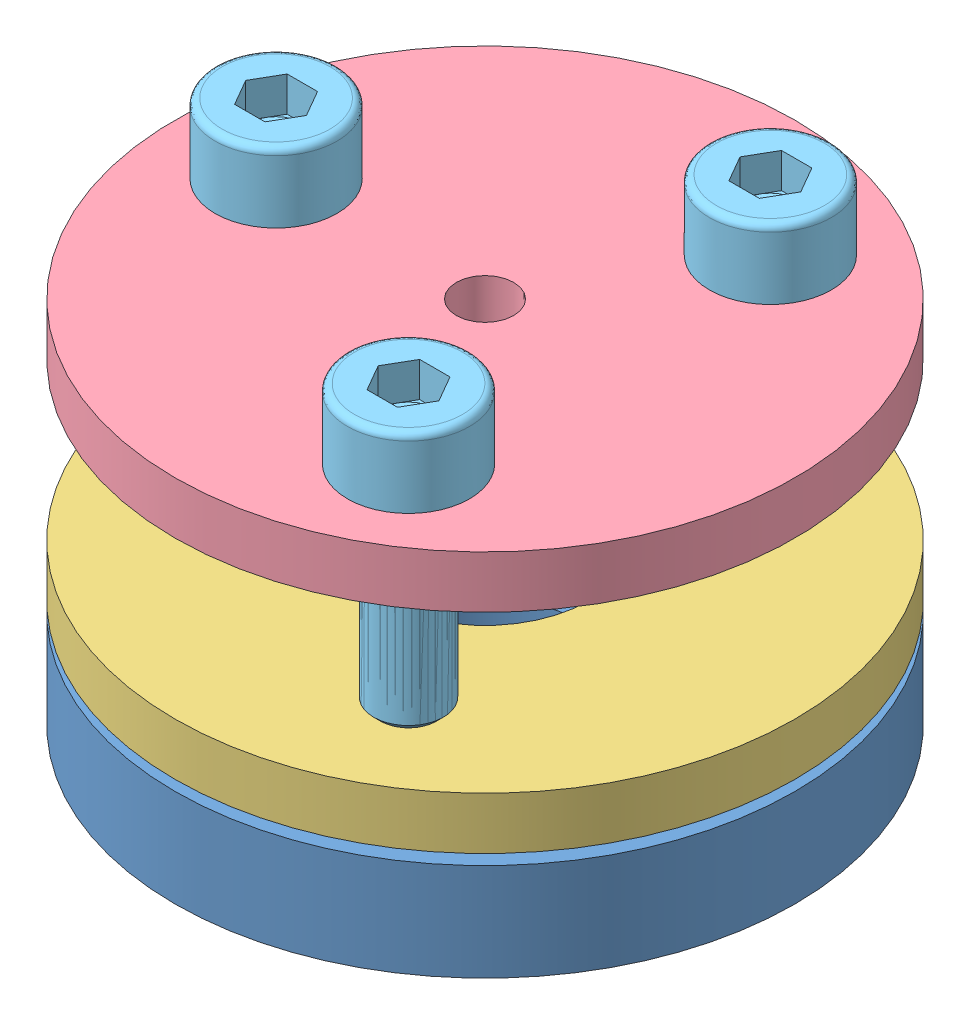
SolidWorks assembly a-spanner-wirbelsäule-v01, configuration 01. Lengths in mm.
Overall size (35.6 25.2 35.6).
8 component instances, 5 part files, 17 mates.
Components (placement in the parent):
- p-federträger-v01-1: p-federträger-v01 [01] at origin size (35.6 5.6 35.6)
- n-tellerfeder-knörzer-A0315-1: n-tellerfeder-knörzer-A0315 [01] at (0 2 0) size (31.5 2.1 31.5)
- n-tellerfeder-knörzer-A0315-2: n-tellerfeder-knörzer-A0315 [01] at (0 6.2 0) x (-1 0 0) z (0 0 1) size (31.5 2.1 31.5)
- p-stützscheibe-v01-1: p-stützscheibe-v01 [01] at (0 6.2 0) size (35.6 3 35.6)
- p-spannscheibe-v01-1: p-spannscheibe-v01 [01] at (0 18.2 0) size (35.6 3 35.6)
- zyl-schr-i6kt-M4x12 (BN4)-5: zyl-schr-i6kt-M4x12 (BN4) [zyl-schr-i6kt-M4x12 (BN4)] at (-12 25.2 0) x (0 -1 0) z (0 0 1) size (16 7 7)
- zyl-schr-i6kt-M4x12 (BN4)-6: zyl-schr-i6kt-M4x12 (BN4) [zyl-schr-i6kt-M4x12 (BN4)] at (6 25.2 -10.3923) x (0 -1 0) z (0 0 1) size (16 7 7)
- zyl-schr-i6kt-M4x12 (BN4)-7: zyl-schr-i6kt-M4x12 (BN4) [zyl-schr-i6kt-M4x12 (BN4)] at (6 25.2 10.3923) x (0 -1 0) z (0 0 1) size (16 7 7)
Mates (geometry in assembly coordinates):
- Deckungsgleich1: coincident anti-aligned: plane of p-federträger-v01-1 through (0 2 15.9) normal (0 1 0); circle of n-tellerfeder-knörzer-A0315-1
- Konzentrisch1: concentric aligned: cylinder of p-federträger-v01-1 through (0 0 0) axis (0 -1 0) radius 15.9; cone of n-tellerfeder-knörzer-A0315-1 through (0 3.7481 0) axis (0 -1 0)
- Parallel1: parallel aligned: plane of n-tellerfeder-knörzer-A0315-1 through (0 2 0) normal (1 0 0); plane of assembly through (0 0 0) normal (1 0 0)
- Deckungsgleich3: coincident anti-aligned: circle of n-tellerfeder-knörzer-A0315-1; circle of n-tellerfeder-knörzer-A0315-2
- Parallel2: parallel anti-aligned: plane of n-tellerfeder-knörzer-A0315-2; plane of assembly through (0 0 0) normal (1 0 0)
- Konzentrisch2: concentric anti-aligned: cone of n-tellerfeder-knörzer-A0315-2 through (0 5.8481 0) axis (0 1 0); cylinder of p-stützscheibe-v01-1 through (0 6.2 0) axis (0 -1 0) radius 6
- Parallel3: parallel aligned: plane of p-stützscheibe-v01-1 through (0 6.2 0) normal (1 0 0); plane of assembly through (0 0 0) normal (1 0 0)
- Abstand1: distance = 9 mm anti-aligned: plane of p-spannscheibe-v01-1 through (0 18.2 1) normal (0 -1 0); plane of p-stützscheibe-v01-1 through (0 9.2 6) normal (0 1 0)
- Konzentrisch3: concentric aligned: cylinder of p-federträger-v01-1 through (0 0 0) axis (0 -1 0) radius 17.8; cylinder of p-spannscheibe-v01-1 through (0 18.2 0) axis (0 -1 0) radius 17.8
- Parallel4: parallel aligned: plane of p-spannscheibe-v01-1 through (0 18.2 0) normal (1 0 0); plane of assembly through (0 0 0) normal (1 0 0)
- Konzentrisch4: concentric aligned: cylinder of p-spannscheibe-v01-1 through (6 21.2 10.3923) axis (0 1 0) radius 1.65; cylinder of zyl-schr-i6kt-M4x12 (BN4)-7 through (6 56.95 10.3923) axis (0 1 0) radius 2
- Deckungsgleich6: coincident anti-aligned: plane of p-stützscheibe-v01-1 through (0 9.2 6) normal (0 1 0); plane of zyl-schr-i6kt-M4x12 (BN4)-7 through (7.61 9.2 10.3923) normal (0 -1 0)
- Konzentrisch5: concentric aligned: cylinder of p-spannscheibe-v01-1 through (-12 21.2 0) axis (0 1 0) radius 1.65; cylinder of zyl-schr-i6kt-M4x12 (BN4)-5 through (-12 56.95 0) axis (0 1 0) radius 2
- Deckungsgleich7: coincident anti-aligned: plane of p-stützscheibe-v01-1 through (0 9.2 6) normal (0 1 0); plane of zyl-schr-i6kt-M4x12 (BN4)-5 through (-10.39 9.2 0) normal (0 -1 0)
- Konzentrisch6: concentric aligned: cylinder of p-spannscheibe-v01-1 through (6 21.2 -10.3923) axis (0 1 0) radius 1.65; cylinder of zyl-schr-i6kt-M4x12 (BN4)-6 through (6 56.95 -10.3923) axis (0 1 0) radius 2
- Deckungsgleich8: coincident anti-aligned: plane of p-stützscheibe-v01-1 through (0 9.2 6) normal (0 1 0); plane of zyl-schr-i6kt-M4x12 (BN4)-6 through (7.61 9.2 -10.3923) normal (0 -1 0)
- Deckungsgleich9: coincident anti-aligned: circle of n-tellerfeder-knörzer-A0315-2; plane of p-stützscheibe-v01-1 through (0 6.2 6) normal (0 -1 0)
